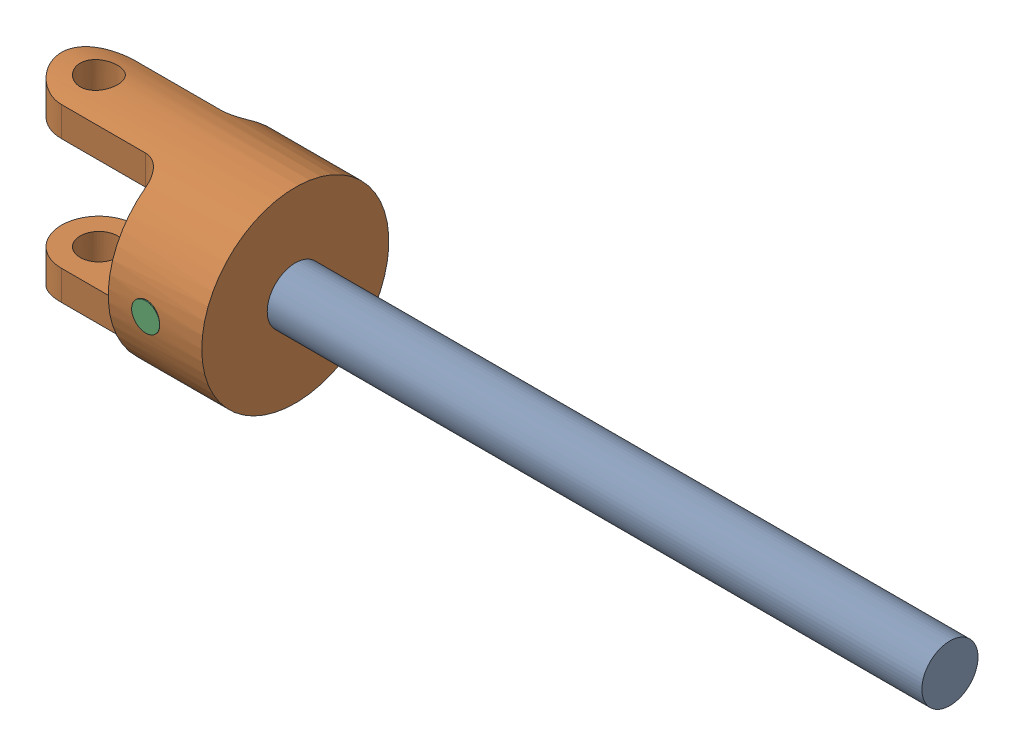
SolidWorks assembly 110303047-93, configuration 預設. Lengths in mm.
Overall size (95 20 20).
3 component instances, 3 part files, 3 mates.
Components (placement in the parent):
- Part-10-1: Part-10 [預設] at (0.492 1.9681 80) size (80 6 6)
- Part-6-1: Part-6 [預設] at (-29.508 1.9681 80) x (0 1 0) z (0 0 1) size (20 25 20)
- Part-7-1: Part-7 [預設] at (-35.508 1.9681 85) x (0 0 -1) z (0.457938 0.888984 0) size (10 3 3)
Mates (geometry in assembly coordinates):
- 同軸心1: concentric anti-aligned: cylinder of 110303047-910-1 through (-35.508 1.9681 77) axis (0 0 1) radius 1.5; cylinder of 110303047-96-1 through (-35.508 1.9681 90) axis (0 0 -1) radius 1.5
- 同軸心2: concentric anti-aligned: cylinder of 110303047-96-1 through (-35.508 1.9681 90) axis (0 0 -1) radius 1.5; cylinder of 110303047-97-1 through (-35.508 1.9681 79.9577) axis (0 0 1) radius 1.5
- 相切1: tangent aligned: cylinder of 110303047-96-1 through (-54.508 1.9681 80) axis (1 0 0) radius 10; plane of 110303047-97-1 through (-35.508 1.9681 90) normal (0 0 1)
